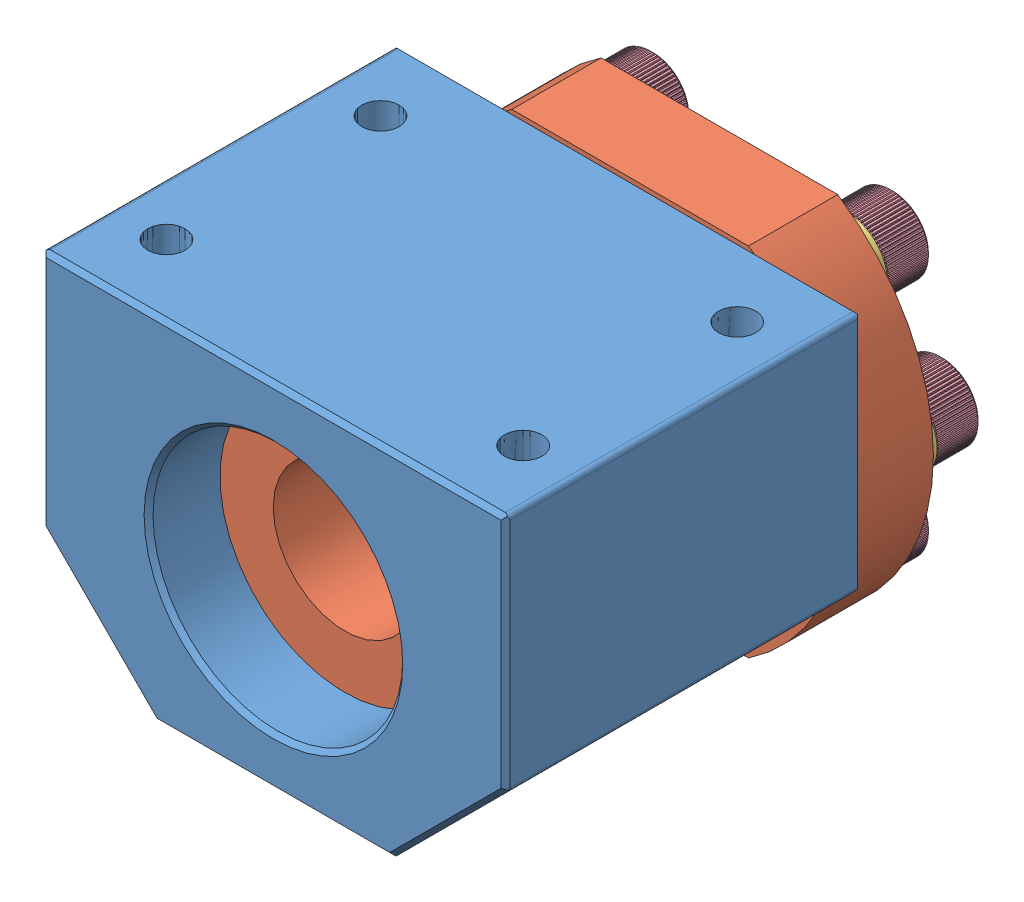
SolidWorks assembly ballscrew_mount, configuration Default. Lengths in mm.
Overall size (52 40 56.23).
14 component instances, 4 part files, 9 mates.
Components (placement in the parent):
- ballscrew_outer_mount-1: ballscrew_outer_mount [Default] at origin size (52 39.5 40)
- ballscrew_center_mount-1: ballscrew_center_mount [Default] at (0 0 -30) x (0 0 1) z (-1 0 0) size (42 40 48)
- m5 washer 98689A114_General Purpose 18-8 Stainless Steel Washer-1: m5 washer 98689A114_General Purpose 18-8 Stainless Steel Washer [98689A114] at (13.435 -13.435 -30.5) x (-1 0 0) z (0 0 -1) size (9 9 1)
- m5x12mm socket 90751A122_18-8 Stainless Steel Socket Head Screws-1: m5x12mm socket 90751A122_18-8 Stainless Steel Socket Head Screws [90751A122] at (13.435 -13.435 -31) x (-1 0 0) z (0 0 1) size (8.5 8.5 17.23)
- m5 washer 98689A114_General Purpose 18-8 Stainless Steel Washer-2: m5 washer 98689A114_General Purpose 18-8 Stainless Steel Washer [98689A114] at (19 0 -30.5) x (-0.707107 -0.707107 0) z (0 0 -1) size (9 9 1)
- m5 washer 98689A114_General Purpose 18-8 Stainless Steel Washer-3: m5 washer 98689A114_General Purpose 18-8 Stainless Steel Washer [98689A114] at (13.435 13.435 -30.5) x (0 -1 0) z (0 0 -1) size (9 9 1)
- m5x12mm socket 90751A122_18-8 Stainless Steel Socket Head Screws-2: m5x12mm socket 90751A122_18-8 Stainless Steel Socket Head Screws [90751A122] at (19 0 -31) x (-0.707107 -0.707107 0) z (0 0 1) size (8.5 8.5 17.23)
- m5x12mm socket 90751A122_18-8 Stainless Steel Socket Head Screws-3: m5x12mm socket 90751A122_18-8 Stainless Steel Socket Head Screws [90751A122] at (13.435 13.435 -31) x (0 -1 0) z (0 0 1) size (8.5 8.5 17.23)
- m5 washer 98689A114_General Purpose 18-8 Stainless Steel Washer-4: m5 washer 98689A114_General Purpose 18-8 Stainless Steel Washer [98689A114] at (-13.435 -13.435 -30.5) x (-1 0 0) z (0 0 -1) size (9 9 1)
- m5x12mm socket 90751A122_18-8 Stainless Steel Socket Head Screws-4: m5x12mm socket 90751A122_18-8 Stainless Steel Socket Head Screws [90751A122] at (-13.435 -13.4342 -31) size (8.5 8.5 17.23)
- m5 washer 98689A114_General Purpose 18-8 Stainless Steel Washer-5: m5 washer 98689A114_General Purpose 18-8 Stainless Steel Washer [98689A114] at (-19 0 -30.5) x (-0.707107 0.707107 0) z (0 0 -1) size (9 9 1)
- m5 washer 98689A114_General Purpose 18-8 Stainless Steel Washer-6: m5 washer 98689A114_General Purpose 18-8 Stainless Steel Washer [98689A114] at (-13.435 13.435 -30.5) x (0 1 0) z (0 0 -1) size (9 9 1)
- m5x12mm socket 90751A122_18-8 Stainless Steel Socket Head Screws-5: m5x12mm socket 90751A122_18-8 Stainless Steel Socket Head Screws [90751A122] at (-18.9994 0.0006 -31) x (0.707107 -0.707107 0) z (0 0 1) size (8.5 8.5 17.23)
- m5x12mm socket 90751A122_18-8 Stainless Steel Socket Head Screws-6: m5x12mm socket 90751A122_18-8 Stainless Steel Socket Head Screws [90751A122] at (-13.435 13.435 -31) x (0 1 0) z (0 0 1) size (8.5 8.5 17.23)
Mates (geometry in assembly coordinates):
- Concentric1: concentric anti-aligned: cylinder of ballscrew_outer_mount-1 through (0 0 20) axis (0 0 -1) radius 14; cylinder of ballscrew_center_mount-1 through (0 0 -20) axis (0 0 1) radius 14
- Coincident1: coincident anti-aligned: plane of ballscrew_outer_mount-1 through (0 0 -20) normal (0 0 -1); plane of ballscrew_center_mount-1 through (0 0 -20) normal (0 0 1)
- Parallel1: parallel aligned: plane of ballscrew_outer_mount-1 through (26 20 20) normal (0 1 0); plane of ballscrew_center_mount-1 through (-13.2665 20 -20) normal (0 1 0)
- Concentric2: concentric anti-aligned: cylinder of m5 washer 98689A114_General Purpose 18-8 Stainless Steel Washer-1 through (13.435 -13.435 -31) axis (0 0 -1) radius 2.65; circle of ballscrew_center_mount-1
- Tangent2: tangent anti-aligned: torus of m5 washer 98689A114_General Purpose 18-8 Stainless Steel Washer-1; plane of m5x12mm socket 90751A122_18-8 Stainless Steel Socket Head Screws-1 through (13.435 -17.43 -31) normal (0 0 1)
- Coincident2: coincident anti-aligned: plane of ballscrew_center_mount-1 through (0 0 -30) normal (0 0 -1); plane of m5 washer 98689A114_General Purpose 18-8 Stainless Steel Washer-1 through (13.435 -10.785 -30) normal (0 0 1)
- Concentric3: concentric anti-aligned: circle of ballscrew_center_mount-1; cylinder of m5 washer 98689A114_General Purpose 18-8 Stainless Steel Washer-1 through (13.435 -13.435 -31) axis (0 0 -1) radius 4.5
- Parallel3: parallel anti-aligned: plane of ballscrew_outer_mount-1 through (26 -6.75 20) normal (1 0 0); plane of m5x12mm socket 90751A122_18-8 Stainless Steel Socket Head Screws-1 through (13.435 -13.435 -31) normal (-1 0 0)
- Parallel4: parallel anti-aligned: plane of ballscrew_outer_mount-1 through (26 -6.75 20) normal (1 0 0); plane of m5 washer 98689A114_General Purpose 18-8 Stainless Steel Washer-1 through (13.435 -13.435 -30.5) normal (-1 0 0)
